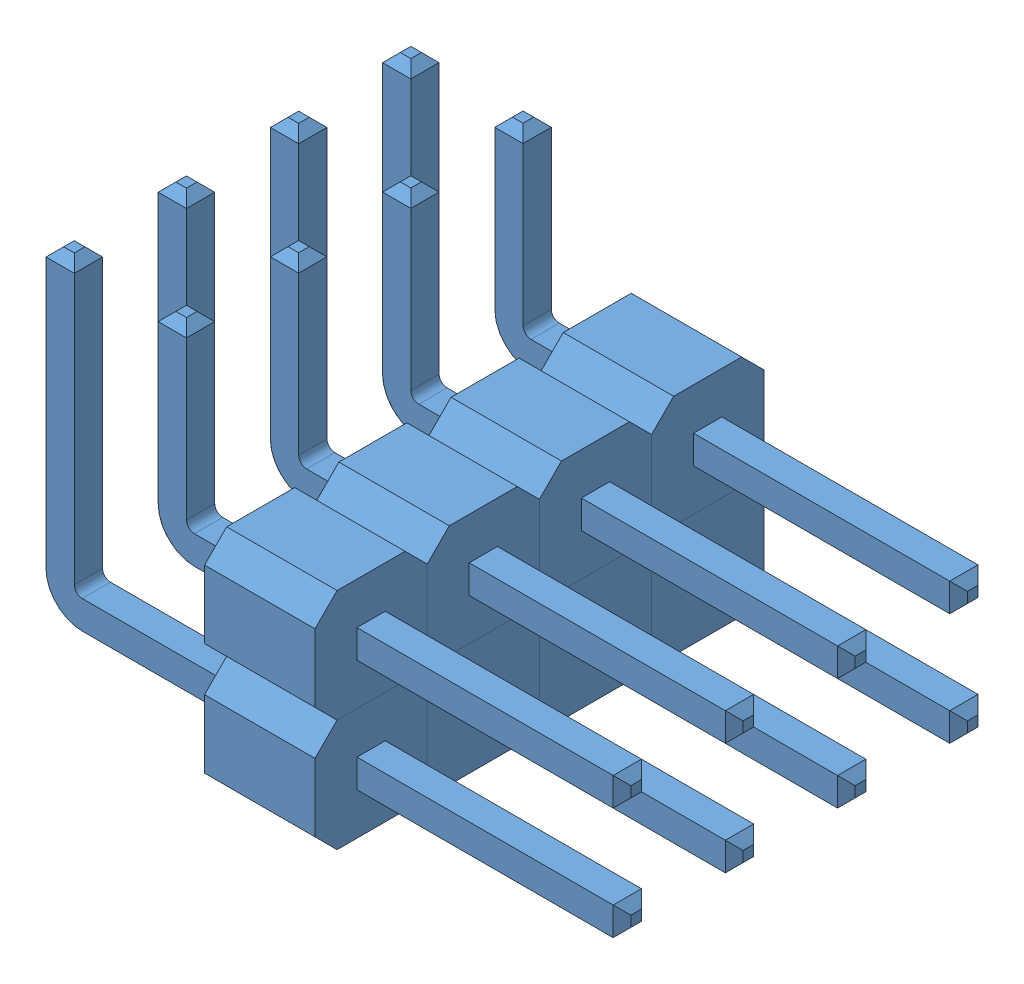
SolidWorks assembly pls_2x4_90_v3, configuration По умолчанию. Lengths in mm.
Overall size (13.04 10.62 10.16).
12 component instances, 1 part files, 9 mates.
Components (placement in the parent):
- pls_2x1_90_v3-1: pls_2x1_90_v3 [По умолчанию] at (-1.4196 0.3392 -0.3778) size (13.04 10.62 2.54)
  - pld90_1_v3-1: pld90_1_v3 [Top] at (5.8512 -3.1222 1.2116) size (13.04 8.08 2.54)
  - pld90_1_v3-2: pld90_1_v3 [По умолчанию] at (5.8512 -0.5822 1.2116) size (13.04 8.08 2.54)
- pls_2x1_90_v3-2: pls_2x1_90_v3 [По умолчанию] at (-1.4196 0.3392 -2.9178) size (13.04 10.62 2.54)
  - pld90_1_v3-1: pld90_1_v3 [Top] at (5.8512 -3.1222 1.2116) size (13.04 8.08 2.54)
  - pld90_1_v3-2: pld90_1_v3 [По умолчанию] at (5.8512 -0.5822 1.2116) size (13.04 8.08 2.54)
- pls_2x1_90_v3-3: pls_2x1_90_v3 [По умолчанию] at (-1.4196 0.3392 -5.4578) size (13.04 10.62 2.54)
  - pld90_1_v3-1: pld90_1_v3 [Top] at (5.8512 -3.1222 1.2116) size (13.04 8.08 2.54)
  - pld90_1_v3-2: pld90_1_v3 [По умолчанию] at (5.8512 -0.5822 1.2116) size (13.04 8.08 2.54)
- pls_2x1_90_v3-4: pls_2x1_90_v3 [По умолчанию] at (-1.4196 0.3392 -7.9978) size (13.04 10.62 2.54)
  - pld90_1_v3-1: pld90_1_v3 [Top] at (5.8512 -3.1222 1.2116) size (13.04 8.08 2.54)
  - pld90_1_v3-2: pld90_1_v3 [По умолчанию] at (5.8512 -0.5822 1.2116) size (13.04 8.08 2.54)
Mates (geometry in assembly coordinates):
- Совпадение1: coincident anti-aligned: plane of pls_2x1_90_v3-1/pld90_1_v3-2 through (-4.0684 1.027 -0.4362) normal (0 0 -1); plane of pls_2x1_90_v3-2/pld90_1_v3-2 through (-4.0684 1.027 -0.4362) normal (0 0 1)
- Совпадение2: coincident aligned: plane of pls_2x1_90_v3-1/pld90_1_v3-2 through (-4.0684 1.027 2.1038) normal (0 1 0); plane of pls_2x1_90_v3-2/pld90_1_v3-2 through (-4.0684 1.027 -0.4362) normal (0 1 0)
- Совпадение3: coincident aligned: plane of pls_2x1_90_v3-1/pld90_1_v3-2 through (-1.5684 -0.243 0.8338) normal (1 0 0); plane of pls_2x1_90_v3-2/pld90_1_v3-2 through (-1.5684 -0.243 -1.7062) normal (1 0 0)
- Совпадение4: coincident anti-aligned: plane of pls_2x1_90_v3-2/pld90_1_v3-2 through (-4.0684 1.027 -2.9762) normal (0 0 -1); plane of pls_2x1_90_v3-3/pld90_1_v3-2 through (-4.0684 1.027 -2.9762) normal (0 0 1)
- Совпадение5: coincident aligned: plane of pls_2x1_90_v3-2/pld90_1_v3-2 through (-4.0684 1.027 -0.4362) normal (0 1 0); plane of pls_2x1_90_v3-3/pld90_1_v3-2 through (-4.0684 1.027 -2.9762) normal (0 1 0)
- Совпадение6: coincident aligned: plane of pls_2x1_90_v3-2/pld90_1_v3-2 through (-1.5684 -0.243 -1.7062) normal (1 0 0); plane of pls_2x1_90_v3-3/pld90_1_v3-2 through (-1.5684 -0.243 -4.2462) normal (1 0 0)
- Совпадение7: coincident anti-aligned: plane of pls_2x1_90_v3-3/pld90_1_v3-2 through (-4.0684 1.027 -5.5162) normal (0 0 -1); plane of pls_2x1_90_v3-4/pld90_1_v3-2 through (-4.0684 1.027 -5.5162) normal (0 0 1)
- Совпадение8: coincident aligned: plane of pls_2x1_90_v3-3/pld90_1_v3-2 through (-4.0684 1.027 -2.9762) normal (0 1 0); plane of pls_2x1_90_v3-4/pld90_1_v3-2 through (-4.0684 1.027 -5.5162) normal (0 1 0)
- Совпадение9: coincident aligned: plane of pls_2x1_90_v3-3/pld90_1_v3-2 through (-1.5684 -0.243 -4.2462) normal (1 0 0); plane of pls_2x1_90_v3-4/pld90_1_v3-2 through (-1.5684 -0.243 -6.7862) normal (1 0 0)
